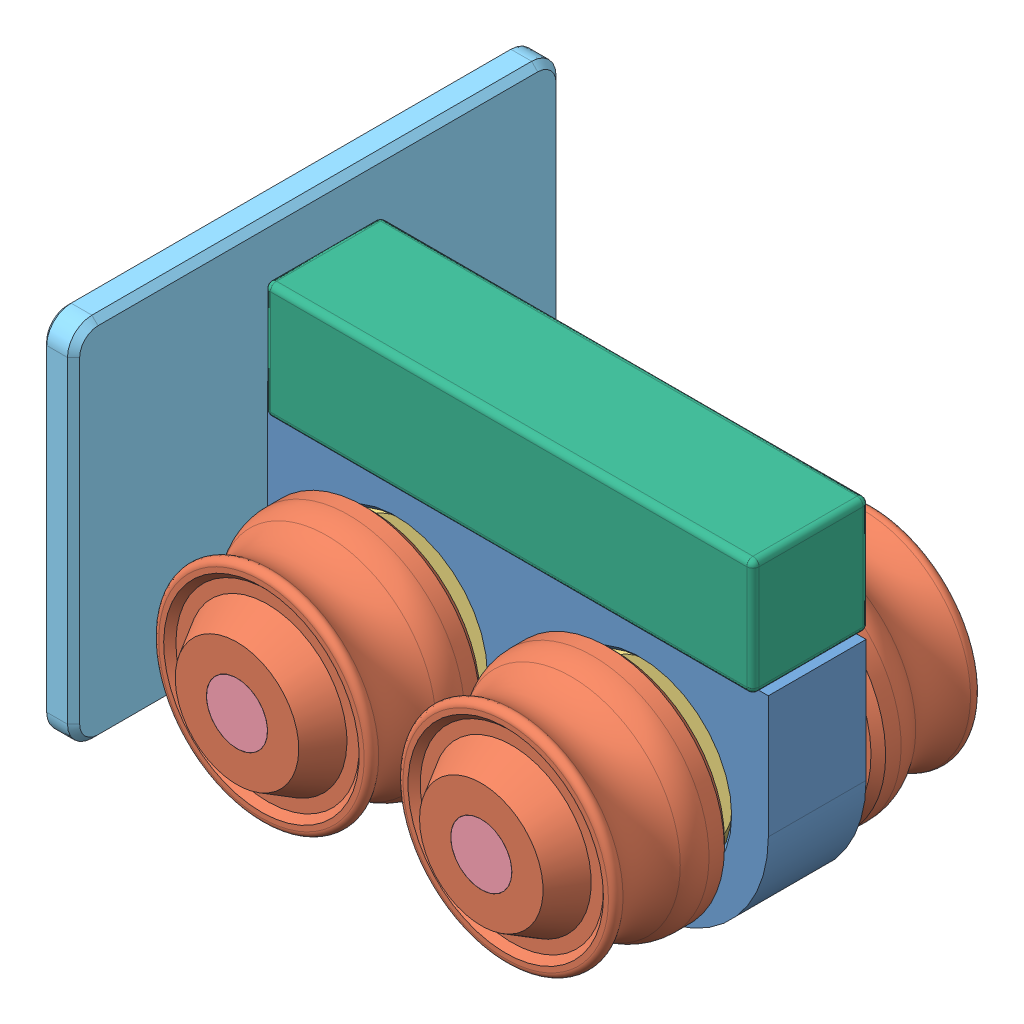
SolidWorks assembly Cart, configuration Default. Lengths in mm.
Overall size (46.27 36.44 40).
11 component instances, 6 part files, 20 mates.
Components (placement in the parent):
- Cart Chassis-1: Cart Chassis [Default] at origin size (42.5 22.5 8)
- Cart Tire-1: Cart Tire [Default] at (0 0 16) x (0 0 1) z (-0.998863 -0.047663 0) size (11 19.01 19.01)
- Cart Tire-2: Cart Tire [Default] at (20 0 16) x (0 0 1) z (-0.999998 -0.001816 0) size (11 19.01 19.01)
- Cart Tire-3: Cart Tire [Default] at (20 0 -8) x (0 0 -1) z (0.583886 0.811836 0) size (11 19.01 19.01)
- Cart Tire-5: Cart Tire [Default] at (0 0 -8) x (0 0 -1) z (0.957716 -0.287717 0) size (11 19.01 19.01)
- 5x14x5 Bushing-10: 5x14x5 Bushing [Default] at (0 0 1.5) x (-0.914169 0.405333 0) z (0 0 1) size (13.75 13.75 5)
- 5x14x5 Bushing-11: 5x14x5 Bushing [Default] at (20 0 1.5) x (-0.914169 0.405333 0) z (0 0 1) size (13.75 13.75 5)
- Cart Axle-1: Cart Axle [Default] at (0 0 -13) x (0.755413 -0.655249 0) z (0 0 1) size (5 5 34)
- Cart Axle-2: Cart Axle [Default] at (20 0 -13) x (0.845954 0.533256 0) z (0 0 1) size (5 5 34)
- Cart Shield-1: Cart Shield [Default] at (-13 8.1762 3.8801) x (0 0 -1) z (1 0 0) size (40 30 2.5)
- Cart Weight-1: Cart Weight [Default] at (30 14.7625 4) x (0 0 1) z (-1 0 0) size (9.53 9.53 40)
Mates (geometry in assembly coordinates):
- Coincident11: coincident anti-aligned: plane of Cart Chassis-1 through (-12 0 8) normal (-1 0 0); plane of Cart Shield-1 through (-12 8.1762 3.8801) normal (1 0 0)
- Concentric1: concentric aligned: cylinder of Cart Chassis-1 through (0 0 8) axis (0 0 -1) radius 7.1; cylinder of 5x14x5 Bushing-10 through (0 0 6.5) axis (0 0 -1) radius 6.875
- Width1: width anti-aligned: plane of Cart Chassis-1 through (0 0 0) normal (0 0 -1); plane of 5x14x5 Bushing-10 through (0 0 8) normal (0 0 1); plane of Cart Chassis-1 through (0 0 6.5) normal (0 0 1); plane of 5x14x5 Bushing-10 through (0 0 1.5) normal (0 0 -1)
- Concentric2: concentric anti-aligned: cylinder of Cart Tire-1 through (0 0 16) axis (0 0 1) radius 2.505; cylinder of Cart Axle-1 through (0 0 21) axis (0 0 -1) radius 2.5
- Concentric3: concentric aligned: cylinder of 5x14x5 Bushing-10 through (0 0 6.5) axis (0 0 -1) radius 2.625; cylinder of Cart Axle-1 through (0 0 21) axis (0 0 -1) radius 2.5
- Coincident12: coincident aligned: plane of Cart Tire-1 through (0 0 21) normal (0 0 1); plane of Cart Axle-1 through (0 0 21) normal (0 0 1)
- Width2: width anti-aligned: plane of Cart Axle-1 through (0 0 21) normal (0 0 1); plane of Cart Chassis-1 through (0 0 -13) normal (0 0 -1); plane of Cart Axle-1 through (0 0 0) normal (0 0 -1); plane of Cart Chassis-1 through (0 0 8) normal (0 0 1)
- Concentric4: concentric aligned: cylinder of Cart Chassis-1 through (20 0 8) axis (0 0 -1) radius 7.1; cylinder of 5x14x5 Bushing-11 through (20 0 6.5) axis (0 0 -1) radius 6.875
- Width3: width anti-aligned: plane of Cart Chassis-1 through (0 0 0) normal (0 0 -1); plane of 5x14x5 Bushing-11 through (0 0 8) normal (0 0 1); plane of Cart Chassis-1 through (20 0 6.5) normal (0 0 1); plane of 5x14x5 Bushing-11 through (20 0 1.5) normal (0 0 -1)
- Width4: width anti-aligned: plane of Cart Axle-2 through (20 0 21) normal (0 0 1); plane of Cart Chassis-1 through (20 0 -13) normal (0 0 -1); plane of Cart Axle-2 through (0 0 0) normal (0 0 -1); plane of Cart Chassis-1 through (0 0 8) normal (0 0 1)
- Concentric5: concentric anti-aligned: cylinder of Cart Tire-2 through (20 0 16) axis (0 0 1) radius 2.505; cylinder of Cart Axle-2 through (20 0 21) axis (0 0 -1) radius 2.5
- Coincident13: coincident aligned: plane of Cart Tire-2 through (20 0 21) normal (0 0 1); plane of Cart Axle-2 through (20 0 21) normal (0 0 1)
- Concentric6: concentric aligned: cylinder of Cart Tire-5 through (0 0 -8) axis (0 0 -1) radius 2.505; cylinder of Cart Axle-1 through (0 0 21) axis (0 0 -1) radius 2.5
- Coincident14: coincident aligned: plane of Cart Tire-5 through (0 0 -13) normal (0 0 -1); plane of Cart Axle-1 through (0 0 -13) normal (0 0 -1)
- Concentric7: concentric aligned: cylinder of Cart Tire-3 through (20 0 -8) axis (0 0 -1) radius 2.505; cylinder of Cart Axle-2 through (20 0 21) axis (0 0 -1) radius 2.5
- Coincident16: coincident aligned: plane of Cart Tire-3 through (20 0 -13) normal (0 0 -1); plane of Cart Axle-2 through (20 0 -13) normal (0 0 -1)
- Concentric8: concentric aligned: cylinder of 5x14x5 Bushing-11 through (20 0 6.5) axis (0 0 -1) radius 2.625; cylinder of Cart Axle-2 through (20 0 21) axis (0 0 -1) radius 2.5
- Coincident19: coincident anti-aligned: plane of Cart Chassis-1 through (-10 10 9) normal (0 1 0); plane of Cart Weight-1 through (-10 10 -0.7625) normal (0 -1 0)
- Width5: width aligned: plane of Cart Weight-1 through (-10 10 8.7625) normal (0 0 1); plane of Cart Chassis-1 through (-10 10 -0.7625) normal (0 0 -1); plane of Cart Weight-1 through (0 0 8) normal (0 0 1); plane of Cart Chassis-1 through (0 0 0) normal (0 0 -1)
- Coincident20: coincident anti-aligned: plane of Cart Chassis-1 through (-10 0 0) normal (1 0 0); plane of Cart Weight-1 through (-10 14.7625 4) normal (-1 0 0)
